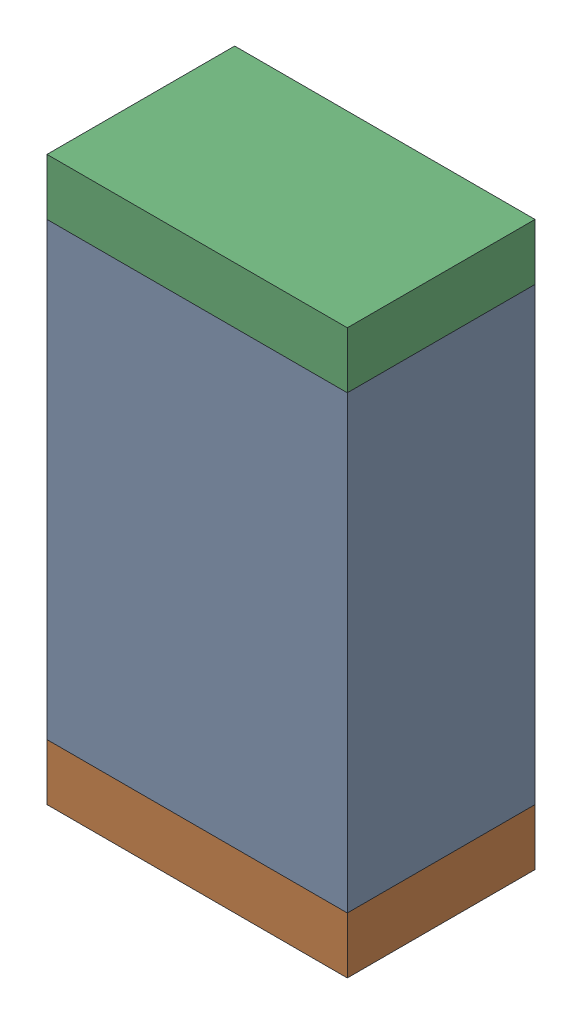
SolidWorks assembly R16, configuration Default. Lengths in mm.
Overall size (0.8 1.5 0.5).
6 component instances, 2 part files, 0 mates.
Components (placement in the parent):
- 810156976-1: 810156976 [Default] at (124.1 40.8 0) size (0.8 1.2 0.5)
  - Extruded_6-1: Extruded_6 [Default] at origin size (0.8 1.2 0.5)
- 810156592-1: 810156592 [Default] at (124.1 40.125 0) size (0.8 0.15 0.5)
  - Extruded_7-1: Extruded_7 [Default] at origin size (0.8 0.15 0.5)
- 810156592-2: 810156592 [Default] at (124.1 41.475 0) size (0.8 0.15 0.5)
  - Extruded_7-1: Extruded_7 [Default] at origin size (0.8 0.15 0.5)
